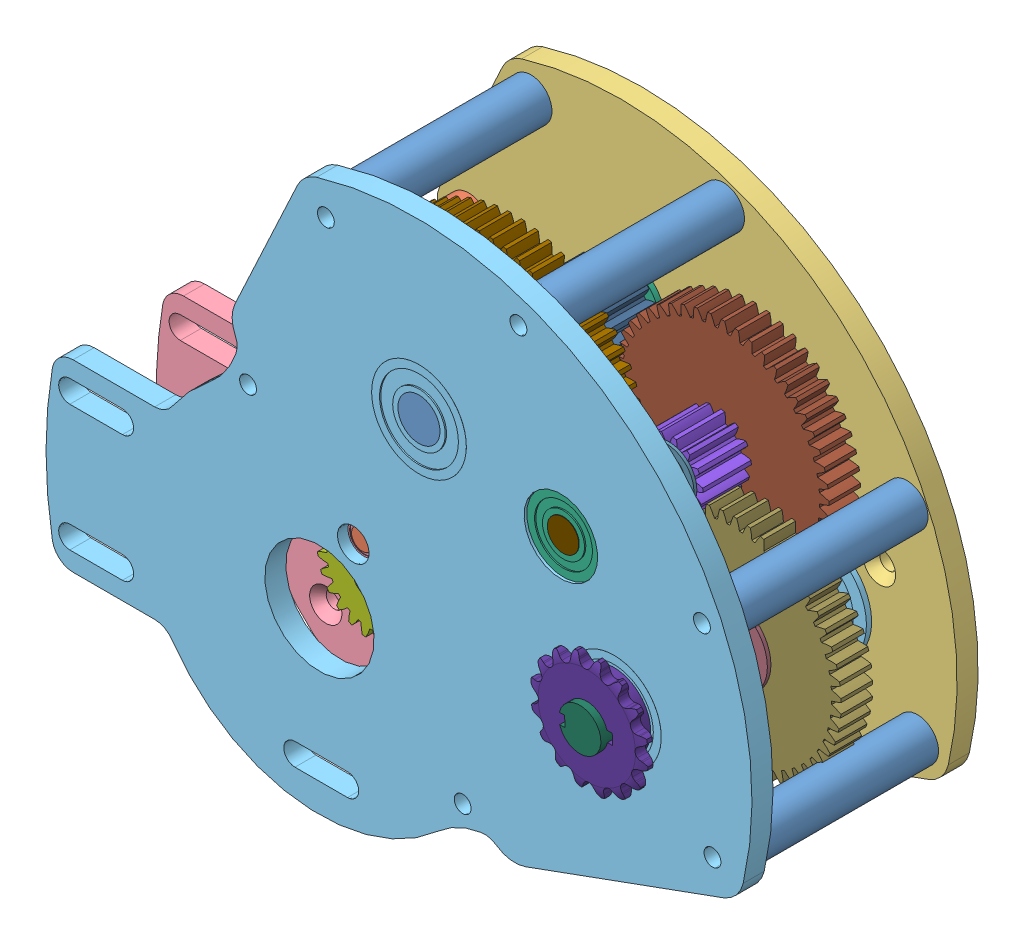
SolidWorks assembly gearbox, configuration Default. Lengths in mm.
Overall size (259.65 226.04 88.06).
40 component instances, 23 part files, 0 mates.
Components (placement in the parent):
- standoff 4-25in-3-1: standoff 4-25in-3 [Default] at (60.071 104.046 72.2313) x (1 0 0) z (0 0 -1) size (12.7 12.7 58.74)
- standoff 4-25in-3-2: standoff 4-25in-3 [Default] at (115.4694 53.8443 72.2313) x (-0.202894 0.979201 0) z (0 0 -1) size (12.7 12.7 58.74)
- standoff 2in-1-1: standoff 2in-1 [Default] at (58.9893 -27.5072 55.5625) x (0.554229 -0.832364 0) z (0 0 -1) size (12.7 12.7 25.4)
- standoff 2in-1-2: standoff 2in-1 [Default] at (-16.8459 62.8697 55.5625) x (0.76538 -0.643578 0) z (0 0 -1) size (12.7 12.7 25.4)
- standoff 1-25in-1-1: standoff 1-25in-1 [Default] at (43.2408 -29.5075 86.5188) x (0.128858 0.991663 0) z (0 0 -1) size (12.7 12.7 30.16)
- standoff 1-25in-1-2: standoff 1-25in-1 [Default] at (-21.5505 47.7078 86.5188) x (0.237698 0.971339 0) z (0 0 -1) size (12.7 12.7 30.16)
- standoff 4-25in-3-3: standoff 4-25in-3 [Default] at (118.6598 -5.7889 72.2313) x (0.71842 0.69561 0) z (0 0 -1) size (12.7 12.7 58.74)
- standoff 4-25in-3-4: standoff 4-25in-3 [Default] at (1.9395 103.1551 72.2313) x (-0.254976 0.966947 0) z (0 0 -1) size (12.7 12.7 58.74)
- fr4-1-1: fr4-1 [Default] at (10.1978 21.8692 71.6915) x (-0.751577 0.659645 0) z (0 0 -1) size (10.72 10.72 3.68)
- fr4-1-2: fr4-1 [Default] at (10.1978 21.8692 101.346) x (0.190518 -0.981684 0) z (0 0 1) size (10.72 10.72 3.68)
- fr8-zz-1-1: fr8-zz-1 [Default] at (88.9055 17.8979 42.056) x (0.807307 0.590132 0) z (0 0 -1) size (31.75 31.75 7.94)
- fr8-zz-1-2: fr8-zz-1 [Default] at (30.0566 64.4566 102.4064) x (0.998387 -0.05677 0) z (0 0 1) size (31.75 31.75 7.94)
- fr8-zz-1-3: fr8-zz-1 [Default] at (88.9055 17.8979 102.4064) x (-0.936963 -0.34943 0) z (0 0 1) size (31.75 31.75 7.94)
- fr6-zz-1-1: fr6-zz-1 [Default] at (30.0566 64.4566 42.4536) x (0.651608 0.758556 0) z (0 0 -1) size (25.4 25.4 7.14)
- fr6-zz-1-2: fr6-zz-1 [Default] at (72.8935 55.2506 42.4536) x (0.430594 0.902546 0) z (0 0 -1) size (25.4 25.4 7.14)
- fr6-zz-1-3: fr6-zz-1 [Default] at (72.8935 55.2506 102.0089) x (-0.227381 0.973806 0) z (0 0 1) size (25.4 25.4 7.14)
- Spur Gear 24t x dd shaft-1: Spur Gear 24t x dd shaft [Default] at (0 0 74.6125) x (-0.989244 0.146277 0) z (0 0 1) size (33.02 33.02 15.88)
- Spur Gear 14t x -375 hex-2-1: Spur Gear 14t x -375 hex-2 [Default] at (10.1978 21.8692 81.4705) x (0.998658 0.051793 0) z (0 0 -1) size (20.03 20.32 15.24)
- Spur Gear 60t x -5 hex-1: Spur Gear 60t x -5 hex [Default] at (30.0566 64.4566 77.7875) x (-0.960646 0.277775 0) z (0 0 1) size (78.74 78.74 9.61)
- Spur Gear 19t x -375 hex-1: Spur Gear 19t x -375 hex [Default] at (30.0566 64.4566 61.2648) x (0.960646 -0.277775 0) z (0 0 -1) size (26.65 26.57 15.24)
- Spur Gear 50t x -375 hex-1: Spur Gear 50t x -375 hex [Default] at (72.8935 55.2506 53.6448) x (0.988008 -0.154401 0) z (0 0 1) size (65.97 66.04 9.49)
- Spur Gear 14t x -375 hex-2-2: Spur Gear 14t x -375 hex-2 [Default] at (72.8935 55.2506 66.3257) x (-0.988008 0.154401 0) z (0 0 -1) size (20.03 20.32 15.24)
- Spur Gear 50t x -5 hex-1: Spur Gear 50t x -5 hex [Default] at (88.9055 17.8979 66.0083) x (-0.03363 0.999434 0) z (0 0 -1) size (65.97 66.04 10.16)
- e-clip -5in shaft-1-1: e-clip -5in shaft-1 [Default] at (30.0566 64.4566 88.4936) x (-0.367411 0.930059 0) z (0 0 1) size (23.88 21.32 1.07)
- e-clip -5in shaft-1-2: e-clip -5in shaft-1 [Default] at (30.0566 64.4566 77.9526) x (-0.980146 0.198276 0) z (0 0 -1) size (23.88 21.32 1.07)
- e-clip -375in shaft-2-1: e-clip -375in shaft-2 [Default] at (30.0566 64.4566 61.849) x (0.99509 -0.098978 0) z (0 0 -1) size (16.76 14.65 0.89)
- e-clip -375in shaft-2-2: e-clip -375in shaft-2 [Default] at (10.1978 21.8692 89.3064) x (0.321675 0.94685 0) z (0 0 -1) size (16.76 14.65 0.89)
- e-clip -375in shaft-2-3: e-clip -375in shaft-2 [Default] at (72.8935 55.2506 48.4251) x (0.215008 0.976612 0) z (0 0 -1) size (16.76 14.65 0.89)
- e-clip -375in shaft-2-4: e-clip -375in shaft-2 [Default] at (72.8935 55.2506 74.1553) x (0.053476 -0.998569 0) z (0 0 1) size (16.76 14.65 0.89)
- e-clip -5in shaft-1-3: e-clip -5in shaft-1 [Default] at (88.9055 17.8979 60.3504) x (0.999831 0.018383 0) z (0 0 -1) size (23.88 21.32 1.07)
- e-clip -5in shaft-1-4: e-clip -5in shaft-1 [Default] at (88.9055 17.8979 71.4502) x (0.998535 -0.05411 0) z (0 0 -1) size (23.88 21.32 1.07)
- output_shaft-1-1: output_shaft-1 [Default] at (88.9055 17.8979 77.3557) x (-0.03363 0.999434 0) z (0 0 1) size (14.66 12.7 78.56)
- encoder mount-1-1: encoder mount-1 [Default] at (89.1821 18.3768 38.1) x (-0.5 -0.866025 0) z (0 0 -1) size (50.8 25.4 9.53)
- Output Sprocket - 16 teeth-1: Output Sprocket - 16 teeth [Default] at (88.9055 17.8979 113.0078) x (-0.03363 0.999434 0) z (0 0 -1) size (35.23 35.23 8.48)
- shaft - step down No- 2 - 0-375 hex-1-1: shaft - step down No- 2 - 0-375 hex-1 [Default] at (72.8935 55.2506 72.3773) x (-0.988008 0.154401 0) z (0 0 1) size (11 9.53 66.67)
- shaft - step down No- 1 - 0-5 hex-1-1: shaft - step down No- 1 - 0-5 hex-1 [Default] at (30.0566 64.4566 72.7075) x (0.960646 -0.277775 0) z (0 0 1) size (14.72 12.75 67.34)
- idler gear shaft-1-1: idler gear shaft-1 [Default] at (10.1978 21.8692 86.233) x (0.998658 0.051793 0) z (0 0 1) size (11 9.53 34.92)
- back plate-1-1: back plate-1 [Default] at (0 0 41.275) x (0.34202 -0.939693 0) z (0 0 1) size (161.34 137.88 6.35)
- motor plate-1-1: motor plate-1 [Default] at (0 0 69.85) x (0.34202 -0.939693 0) z (0 0 1) size (126.75 137.54 6.35)
- front plate-1-1: front plate-1 [Default] at (0 0 103.1875) x (0.34202 -0.939693 0) z (0 0 1) size (161.34 217.59 6.35)
